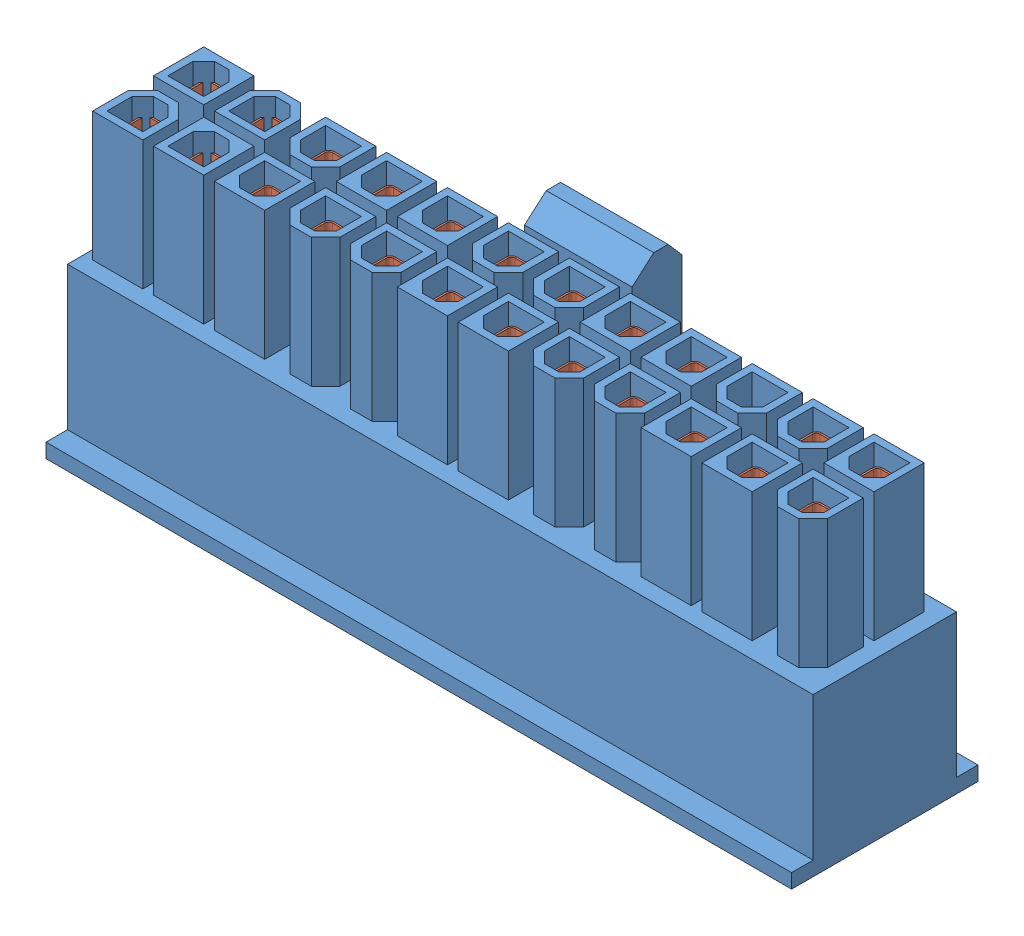
SolidWorks assembly Baugruppe1, configuration Standard. Lengths in mm.
Overall size (52 21 15).
24 component instances, 2 part files, 3 mates.
Components (placement in the parent):
- ATX-Main-24-Pin-Body-1: ATX-Main-24-Pin-Body [Standard] at (18.8663 27.4781 43.7221) size (52 21 15)
- ATX-Main-24-Pin-crimp-1: ATX-Main-24-Pin-crimp [Standard] at (41.9913 37.2033 42.6221) x (0 1 0) z (-1 0 0) size (15.03 2.9 3.08)
- ATX-Main-24-Pin-crimp-2: ATX-Main-24-Pin-crimp [Standard] at (41.9913 37.2033 46.8721) x (0 1 0) z (-1 0 0) size (15.03 2.9 3.08)
- ATX-Main-24-Pin-crimp-3: ATX-Main-24-Pin-crimp [Standard] at (37.7413 37.2033 42.6221) x (0 1 0) z (-1 0 0) size (15.03 2.9 3.08)
- ATX-Main-24-Pin-crimp-4: ATX-Main-24-Pin-crimp [Standard] at (37.7413 37.2033 46.8721) x (0 1 0) z (-1 0 0) size (15.03 2.9 3.08)
- ATX-Main-24-Pin-crimp-6: ATX-Main-24-Pin-crimp [Standard] at (33.4913 37.2033 46.8721) x (0 1 0) z (-1 0 0) size (15.03 2.9 3.08)
- ATX-Main-24-Pin-crimp-7: ATX-Main-24-Pin-crimp [Standard] at (29.2413 37.2033 42.6221) x (0 1 0) z (-1 0 0) size (15.03 2.9 3.08)
- ATX-Main-24-Pin-crimp-8: ATX-Main-24-Pin-crimp [Standard] at (29.2413 37.2033 46.8721) x (0 1 0) z (-1 0 0) size (15.03 2.9 3.08)
- ATX-Main-24-Pin-crimp-9: ATX-Main-24-Pin-crimp [Standard] at (24.9913 37.2033 42.6221) x (0 1 0) z (-1 0 0) size (15.03 2.9 3.08)
- ATX-Main-24-Pin-crimp-10: ATX-Main-24-Pin-crimp [Standard] at (24.9913 37.2033 46.8721) x (0 1 0) z (-1 0 0) size (15.03 2.9 3.08)
- ATX-Main-24-Pin-crimp-11: ATX-Main-24-Pin-crimp [Standard] at (20.7413 37.2033 42.6221) x (0 1 0) z (-1 0 0) size (15.03 2.9 3.08)
- ATX-Main-24-Pin-crimp-12: ATX-Main-24-Pin-crimp [Standard] at (20.7413 37.2033 46.8721) x (0 1 0) z (-1 0 0) size (15.03 2.9 3.08)
- ATX-Main-24-Pin-crimp-13: ATX-Main-24-Pin-crimp [Standard] at (16.4913 37.2033 42.6221) x (0 1 0) z (-1 0 0) size (15.03 2.9 3.08)
- ATX-Main-24-Pin-crimp-14: ATX-Main-24-Pin-crimp [Standard] at (16.4913 37.2033 46.8721) x (0 1 0) z (-1 0 0) size (15.03 2.9 3.08)
- ATX-Main-24-Pin-crimp-15: ATX-Main-24-Pin-crimp [Standard] at (12.2413 37.2033 42.6221) x (0 1 0) z (-1 0 0) size (15.03 2.9 3.08)
- ATX-Main-24-Pin-crimp-16: ATX-Main-24-Pin-crimp [Standard] at (12.2413 37.2033 46.8721) x (0 1 0) z (-1 0 0) size (15.03 2.9 3.08)
- ATX-Main-24-Pin-crimp-17: ATX-Main-24-Pin-crimp [Standard] at (7.9913 37.2033 42.6221) x (0 1 0) z (-1 0 0) size (15.03 2.9 3.08)
- ATX-Main-24-Pin-crimp-18: ATX-Main-24-Pin-crimp [Standard] at (7.9913 37.2033 46.8721) x (0 1 0) z (-1 0 0) size (15.03 2.9 3.08)
- ATX-Main-24-Pin-crimp-19: ATX-Main-24-Pin-crimp [Standard] at (3.7413 37.2033 42.6221) x (0 1 0) z (-1 0 0) size (15.03 2.9 3.08)
- ATX-Main-24-Pin-crimp-20: ATX-Main-24-Pin-crimp [Standard] at (3.7413 37.2033 46.8721) x (0 1 0) z (-1 0 0) size (15.03 2.9 3.08)
- ATX-Main-24-Pin-crimp-21: ATX-Main-24-Pin-crimp [Standard] at (-0.5087 37.2033 42.6221) x (0 1 0) z (-1 0 0) size (15.03 2.9 3.08)
- ATX-Main-24-Pin-crimp-22: ATX-Main-24-Pin-crimp [Standard] at (-0.5087 37.2033 46.8721) x (0 1 0) z (-1 0 0) size (15.03 2.9 3.08)
- ATX-Main-24-Pin-crimp-23: ATX-Main-24-Pin-crimp [Standard] at (-4.7587 37.2033 42.6221) x (0 1 0) z (-1 0 0) size (15.03 2.9 3.08)
- ATX-Main-24-Pin-crimp-24: ATX-Main-24-Pin-crimp [Standard] at (-4.7587 37.2033 46.8721) x (0 1 0) z (-1 0 0) size (15.03 2.9 3.08)
Mates (geometry in assembly coordinates):
- Abstand2: distance = 0.225 mm anti-aligned: plane of ATX-Main-24-Pin-crimp-1 through (43.0163 37.2033 42.6221) normal (1 0 0); plane of ATX-Main-24-Pin-Body-1 through (43.2413 27.4781 42.0971) normal (-1 0 0)
- Deckungsgleich4: coincident anti-aligned: plane of ATX-Main-24-Pin-Body-1 through (65.6163 37.4781 43.7221) normal (0 -1 0); plane of ATX-Main-24-Pin-crimp-1 through (40.9663 37.4781 39.7221) normal (0 1 0)
- Deckungsgleich5: coincident anti-aligned: plane of ATX-Main-24-Pin-Body-1 through (40.1163 37.4781 39.7221) normal (0 0 1); plane of ATX-Main-24-Pin-crimp-1 through (41.9913 37.2033 39.7221) normal (0 0 -1)
